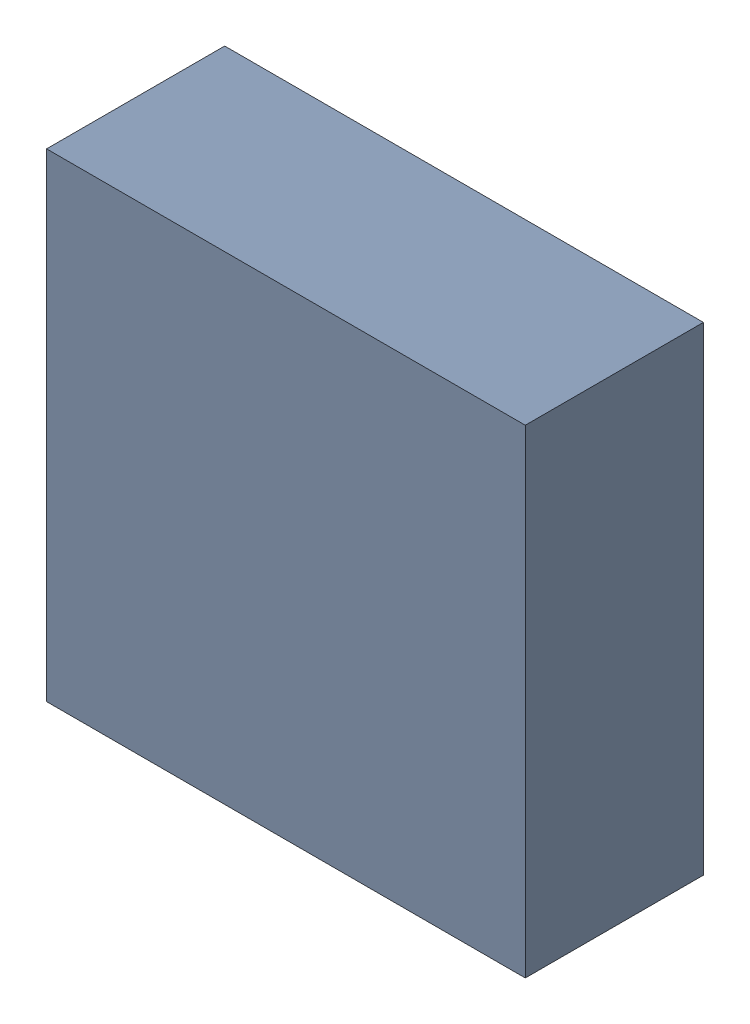
SolidWorks assembly Q7, configuration ﾃﾞﾌｫﾙﾄ. Lengths in mm.
Overall size (2.15 2.15 0.8).
2 component instances, 1 part files, 0 mates.
Components (placement in the parent):
- 689261240-1: 689261240 [ﾃﾞﾌｫﾙﾄ] at (17.5 73.25 0) size (2.15 2.15 0.8)
  - Extruded_30-1: Extruded_30 [ﾃﾞﾌｫﾙﾄ] at origin size (2.15 2.15 0.8)
